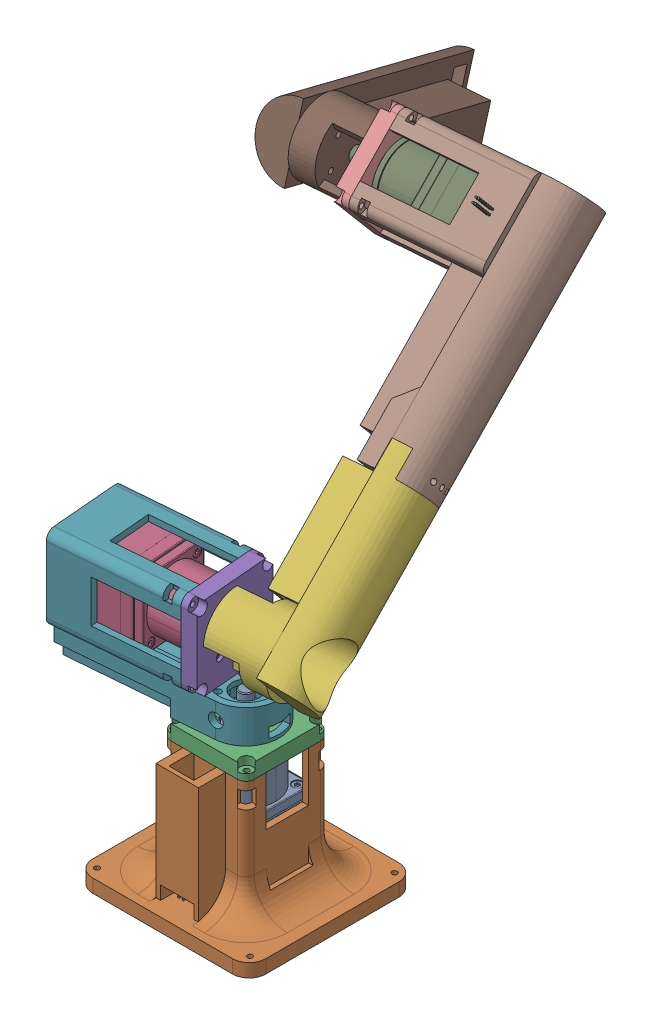
SolidWorks assembly Arm_Assem, configuration 默认. Lengths in mm.
Overall size (185.67 309.04 317.02).
12 component instances, 7 part files, 28 mates.
Components (placement in the parent):
- motor-1: motor [默认] at (-23.7899 3.4398 222.5934) x (1 0 0) z (0 1 0) size (42.32 60.31 95.01)
- base1-1: base1 [默认] at (-23.8799 -33.5602 222.5034) size (104 78 100)
- Base2-1: Base2 [默认] at (-23.7899 44.4398 222.5934) size (50 9 50)
- motor-2: motor [默认] at (-79.5928 98.4398 227.2882) x (-0.083836 0 -0.99648) z (0.99648 0 -0.083836) size (42.32 60.31 95.01)
- Base2-2: Base2 [默认] at (-38.7371 98.4398 223.8509) x (0.083836 0 0.99648) z (0 1 0) size (50 9 50)
- Link2-1: Link2 [默认] at (-29.7688 98.4398 223.0964) x (0.99648 0 -0.083836) z (-0.063606 0.651447 -0.756023) size (56 42 121)
- link1-2: link1 [默认] at (-38.7371 98.4398 223.8509) x (0.99648 0 -0.083836) z (0.083836 0 0.99648) size (110 70 50)
- link2.2-2: link2.2 [默认] at (-82.6672 231.9864 71.4651) x (-0.99648 0 0.083836) z (-0.054615 -0.758694 -0.649154) size (96 145.05 50)
- motor-3: motor [默认] at (-41.8009 231.9961 68.1543) x (-0.063606 0.651447 -0.756023) z (-0.99648 0 0.083836) size (42.32 60.31 95.01)
- Base2-3: Base2 [默认] at (-82.6672 231.9864 71.4651) x (0.054615 0.758694 0.649154) z (0.063606 -0.651447 0.756023) size (50 9 50)
- Link2-2: Link2 [默认] at (-91.6249 231.9961 72.3461) x (-0.99648 0 0.083836) z (-0.08 -0.299039 -0.950881) size (56 42 121)
- GripperLink2-2: GripperLink2 [Default] at (-119.4051 186.7813 -18.1562) x (0.99648 0 -0.083836) z (-0.02507 0.954241 -0.297987) size (71 30 42) (suppressed, hidden)
Mates (geometry in assembly coordinates):
- Coincident1: coincident anti-aligned: plane of motor-1 through (-23.7899 -25.5602 222.5934) normal (0 -1 0); plane of base1-1 through (-23.8799 -25.5602 222.5034) normal (0 1 0)
- Coincident2: coincident anti-aligned: plane of motor-1 through (-2.6299 67.2893 209.2797) normal (1 0 0); plane of base1-1 through (-2.6299 44.4398 243.7534) normal (-1 0 0)
- Coincident3: coincident anti-aligned: plane of motor-1 through (-37.1036 67.2893 243.7534) normal (0 0 1); plane of base1-1 through (-45.1299 44.4398 243.7534) normal (0 0 -1)
- Concentric1: concentric aligned: cylinder of motor-1 through (-23.7899 49.4398 222.5934) axis (0 -1 0) radius 18; cylinder of Base2-1 through (-23.7899 49.9398 222.5934) axis (0 -1 0) radius 18.25
- Parallel1: parallel aligned: plane of base1-1 through (1.1201 44.4398 247.5034) normal (1 0 0); plane of Base2-1 through (1.2101 56.4398 247.5934) normal (1 0 0)
- Coincident4: coincident anti-aligned: plane of base1-1 through (-23.8799 44.4398 222.5034) normal (0 1 0); plane of Base2-1 through (-23.7899 44.4398 222.5934) normal (0 -1 0)
- Concentric4: concentric aligned: circle of motor-2; cylinder of Base2-2 through (-23.2917 98.4398 222.5515) axis (-0.99648 0 0.083836) radius 11.25
- Coincident11: coincident anti-aligned: plane of Base2-2 through (-29.7688 98.4398 223.0964) normal (0.99648 0 -0.083836); plane of Link2-1 through (-29.7688 98.4398 223.0964) normal (-0.99648 0 0.083836)
- Coincident12: coincident anti-aligned: plane of motor-2 through (-108.4907 98.4398 229.7195) normal (-0.99648 0 0.083836); plane of link1-2 through (-108.4907 98.4398 229.7195) normal (0.99648 0 -0.083836)
- Concentric6: concentric aligned: cylinder of Base2-2 through (-39.8822 120.0398 246.025) axis (0.99648 0 -0.083836) radius 1.55; cylinder of link1-2 through (-41.8751 120.0398 246.1927) axis (0.99648 0 -0.083836) radius 1.55
- Coincident13: coincident anti-aligned: plane of Base2-2 through (-38.7371 98.4398 223.8509) normal (-0.99648 0 0.083836); plane of link1-2 through (-38.7371 98.4398 223.8509) normal (0.99648 0 -0.083836)
- Coincident15: coincident anti-aligned: plane of Base2-1 through (-23.7899 53.4398 222.5934) normal (0 1 0); plane of link1-2 through (-38.7371 53.4398 223.8509) normal (0 -1 0)
- Coincident16: coincident anti-aligned: plane of Link2-1 through (10.6748 167.823 167.0492) normal (0.99648 0 -0.083836); plane of link2.2-2 through (7.7036 149.5743 131.7341) normal (-0.99648 0 0.083836)
- Coincident17: coincident anti-aligned: plane of Link2-1 through (-0.2985 153.8128 155.9002) normal (-0.063606 0.651447 -0.756023); plane of link2.2-2 through (-0.2985 153.8128 155.9002) normal (0.063606 -0.651447 0.756023)
- Coincident18: coincident aligned: line of Link2-1 through (3.9611 82.5072 206.5299) axis (-0.063606 0.651447 -0.756023); line of link2.2-2 through (-3.9897 163.9381 112.027) axis (-0.063606 0.651447 -0.756023)
- Concentric8: concentric aligned: cylinder of Base2-2 through (-43.571 120.0398 202.1799) axis (0.99648 0 -0.083836) radius 1.55; cylinder of link1-2 through (-45.5639 120.0398 202.3476) axis (0.99648 0 -0.083836) radius 1.55
- Coincident19: coincident anti-aligned: plane of link2.2-2 through (-12.9137 231.9864 65.5966) normal (-0.99648 0 0.083836); plane of motor-3 through (-12.903 231.9961 65.723) normal (0.99648 0 -0.083836)
- Coincident20: coincident anti-aligned: plane of link2.2-2 through (-12.7226 202.0209 67.8675) normal (-0.063606 0.651447 -0.756023); plane of motor-3 through (-103.3526 228.3125 98.1473) normal (0.063606 -0.651447 0.756023)
- Coincident21: coincident anti-aligned: plane of link2.2-2 through (-10.4015 234.2654 95.4566) normal (-0.054615 -0.758694 -0.649154); plane of motor-3 through (-103.4232 239.3769 97.3087) normal (0.054615 0.758694 0.649154)
- Concentric11: concentric aligned: cylinder of link2.2-2 through (-77.5125 201.2239 73.0946) axis (-0.99648 0 0.083836) radius 1.55; cylinder of Base2-3 through (-79.5054 201.2239 73.2623) axis (-0.99648 0 0.083836) radius 1.55
- Coincident22: coincident anti-aligned: plane of link2.2-2 through (-82.6672 231.9864 71.4651) normal (-0.99648 0 0.083836); plane of Base2-3 through (-82.6672 231.9864 71.4651) normal (0.99648 0 -0.083836)
- Concentric13: concentric aligned: cylinder of link2.2-2 through (-80.2603 229.3664 40.4344) axis (-0.99648 0 0.083836) radius 1.55; cylinder of Base2-3 through (-82.2532 229.3664 40.6021) axis (-0.99648 0 0.083836) radius 1.55
- Concentric14: concentric aligned: cylinder of motor-3 through (-107.5686 231.9961 73.6875) axis (0.99648 0 -0.083836) radius 4; cylinder of Link2-2 through (-111.5545 231.9961 74.0228) axis (0.99648 0 -0.083836) radius 16.75
- Concentric15: concentric aligned: cylinder of motor-1 through (-23.7899 69.4398 222.5934) axis (0 -1 0) radius 4; cylinder of link1-2 through (-23.7899 65.4398 222.5934) axis (0 -1 0) radius 16.25
- Concentric16: concentric aligned: cylinder of motor-2 through (-13.8251 98.4398 221.755) axis (-0.99648 0 0.083836) radius 4; cylinder of Link2-1 through (5.108 98.4398 220.1621) axis (-0.99648 0 0.083836) radius 21
- Coincident23: coincident anti-aligned: plane of Base2-3 through (-91.6356 231.9864 72.2196) normal (-0.99648 0 0.083836); plane of Link2-2 through (-91.6249 231.9961 72.3461) normal (0.99648 0 -0.083836)
- Concentric17: concentric aligned: cylinder of Link2-2 through (-125.0617 237.3788 92.3962) axis (-0.08 -0.299039 -0.950881) radius 21; cylinder of GripperLink2-2 through (-130.3256 217.7024 29.8297) axis (-0.08 -0.299039 -0.950881) radius 21
- Concentric18: concentric aligned: cylinder of Link2-2 through (-147.8524 204.3349 -11.5025) axis (0.99648 0 -0.083836) radius 1.55; cylinder of GripperLink2-2 through (-151.3401 204.3349 -11.209) axis (0.99648 0 -0.083836) radius 1.55
